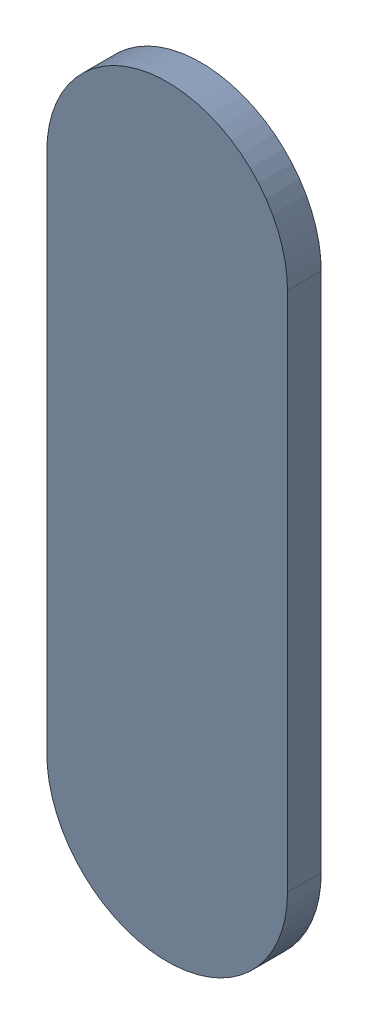
SolidWorks assembly Track (31.8mm,40.15mm)(31.8mm,40.7mm) on Top Layer, configuration Predeterminado. Lengths in mm.
Overall size (0.25 0.8 0.04).
2 component instances, 1 part files, 0 mates.
Components (placement in the parent):
- Track (31.8mm,40.15mm)(31.8mm,40.7mm) on Top Layer-1-1: Track (31.8mm,40.15mm)(31.8mm,40.7mm) on Top Layer-1 [Predeterminado] at (-68.317 -44.187 -0.0457) size (0.25 0.8 0.04)
  - Track (31.8mm,40.15mm)(31.8mm,40.7mm) on Top Layer-Part-1-1: Track (31.8mm,40.15mm)(31.8mm,40.7mm) on Top Layer-Part-1 [Predeterminado] at origin size (0.25 0.8 0.04)
